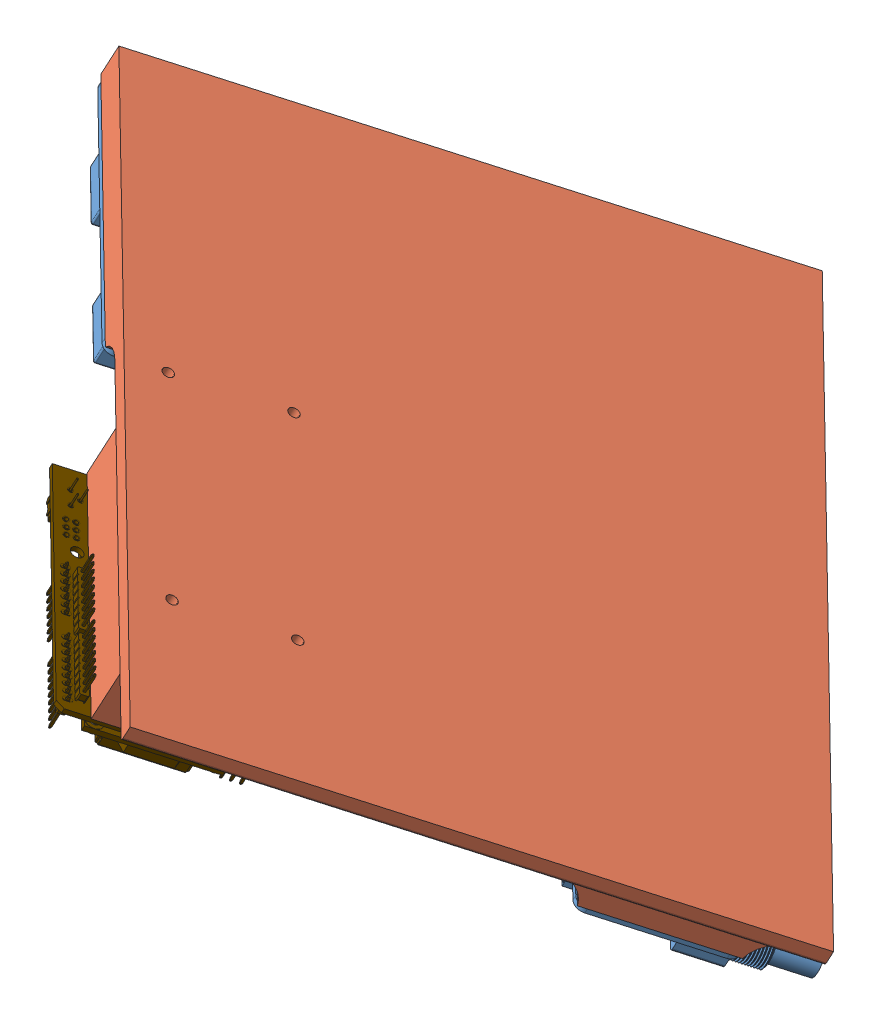
SolidWorks assembly growbox autorefill assembly, configuration Default. Lengths in mm.
Overall size (280.11 145.93 288.18).
73 component instances, 37 part files, 15 mates.
Components (placement in the parent):
- RelayClean.stp-1: RelayClean.stp [Default] at (-109.2702 -103.904 46.5137) x (0.587517 -0.410523 -0.697348) z (-0.706078 0.160923 -0.689606) size (177.8 17.08 90.17)
- growbox autorefill base-1: growbox autorefill base [Default] at (-84.2153 -124.6616 -49.3614) x (0.706078 -0.160923 0.689606) z (0.587517 -0.410523 -0.697348) size (224.54 40 180)
- Arduino MEGA 2560 R3.STEP-1: Arduino MEGA 2560 R3.STEP [Default] at (14.5549 -162.184 63.1118) x (0.706078 -0.160923 0.689606) z (0.587517 -0.410523 -0.697348) size (53.34 15.25 107.96)
  - MEGAboard.STEP-1: MEGAboard.STEP [Default] at origin size (53.34 1.6 101.6)
  - 47uf CAP Dcase.STEP-1: 47uf CAP Dcase.STEP [Default] at (-9.144 0 -18.415) x (0 0 -1) z (1 0 0) size (7.2 5.81 8)
  - USB SHELL.STEP-1: USB SHELL.STEP [Default] at (-38.02 0.43 6.35) size (14.09 15.2 16.51)
  - USB core.STEP-1: USB core.STEP [Default] at (-38.02 0.43 6.35) size (11.3 10.68 15.75)
  - usb top contact.STEP-1: usb top contact.STEP [Default] at (-36.77 6.52 5.97) size (1 9.67 13.76)
  - usb btm contact.STEP-1: usb btm contact.STEP [Default] at (-36.77 4.84 5.97) size (1 6.84 11.76)
  - usb btm contact.STEP-2: usb btm contact.STEP [Default] at (-39.27 4.84 5.97) size (1 6.84 11.76)
  - usb top contact.STEP-2: usb top contact.STEP [Default] at (-39.27 6.52 5.97) size (1 9.67 13.76)
  - power jack.STEP-1: power jack.STEP [Default] at (-7.675 0 1.905) size (11.2 15.2 15.9)
  - 47uf CAP Dcase.STEP-2: 47uf CAP Dcase.STEP [Default] at (-9.144 0 -25.527) x (0 0 -1) z (1 0 0) size (7.2 5.81 8)
  - crystal.STEP-1: crystal.STEP [Default] at (-26.035 0 -18.415) x (1 0 0) z (0 0 -1) size (4 5 11)
  - 2pin_header__02.STEP-1: 2pin_header__02.STEP [Default] at (-46.23 0 -15.75) size (5 11.75 2.54)
  - reg.STEP-1: reg.STEP [Default] at (-17.78 0 -8.636) size (6.5 1.69 8.3)
  - led.STEP-1: led.STEP [Default] at (-34.29 0 -27.94) x (0 0 1) z (-1 0 0) size (4.01 0.9 1.56)
  - 2pin_header__02.STEP-2: 2pin_header__02.STEP [Default] at (-30.43 0 -64.91) x (0 0 1) z (-1 0 0) size (5 11.75 2.54)
  - 2pin_header__02.STEP-3: 2pin_header__02.STEP [Default] at (-27.89 0 -64.91) x (0 0 1) z (-1 0 0) size (5 11.75 2.54)
  - 2pin_header__02.STEP-4: 2pin_header__02.STEP [Default] at (-25.35 0 -64.91) x (0 0 1) z (-1 0 0) size (5 11.75 2.54)
  - 2pin_header__02.STEP-5: 2pin_header__02.STEP [Default] at (-46.23 0 -18.29) size (5 11.75 2.54)
  - 2pin_header__02.STEP-6: 2pin_header__02.STEP [Default] at (-46.23 0 -20.83) size (5 11.75 2.54)
  - atmega16u2.STEP-1: atmega16u2.STEP [Default] at (-34.671 0.06 -20) x (1 0 0) z (0 0 -1) size (5.5 1.01 5.5)
  - led.STEP-2: led.STEP [Default] at (-36.576 0 -27.94) x (0 0 -1) z (1 0 0) size (4.01 0.9 1.56)
  - led.STEP-3: led.STEP [Default] at (-42.164 0 -27.94) x (0 0 1) z (-1 0 0) size (4.01 0.9 1.56)
  - led.STEP-4: led.STEP [Default] at (-36.83 0 -76.2) x (0 0 1) z (-1 0 0) size (4.01 0.9 1.56)
  - 8 PORT HEADER.STEP-1: 8 PORT HEADER.STEP [Default] at (-50.8 0 -45.72) x (0 0 -1) z (1 0 0) size (20.32 10.51 2.41)
  - 8 PORT HEADER.STEP-2: 8 PORT HEADER.STEP [Default] at (-2.54 0 -27.94) x (0 0 -1) z (1 0 0) size (20.32 10.51 2.41)
  - 8 PORT HEADER.STEP-3: 8 PORT HEADER.STEP [Default] at (-2.54 0 -50.8) x (0 0 -1) z (1 0 0) size (20.32 10.51 2.41)
  - 10 PORT HEADER.STEP-1: 10 PORT HEADER.STEP [Default] at (-50.8 0 -18.796) x (0 0 -1) z (1 0 0) size (25.4 10.51 2.41)
  - 102 RESISTOR PACK.STEP-1: 102 RESISTOR PACK.STEP [Default] at (-36.83 0 -80.645) size (3.2 0.51 3)
  - 102 RESISTOR PACK.STEP-2: 102 RESISTOR PACK.STEP [Default] at (-39.37 0 -27.94) size (3.2 0.51 3)
  - 103 RESISTOR PACK.STEP-1: 103 RESISTOR PACK.STEP [Default] at (-31.115 0 -27.94) size (3.2 0.51 3)
  - 220 RESISTOR PACK.STEP-1: 220 RESISTOR PACK.STEP [Default] at (-37.084 0 -12.065) size (3.2 0.51 3)
  - 16mhz crystal - measured.STEP-1: 16mhz crystal - measured.STEP [Default] at (-14.605 0 -38.354) size (3.4 0.8 2)
  - PADS001.STEP-1: PADS001.STEP [Default] at (-39.878 0.1 -18.288) x (-1 0 0) z (0 0 1) size (4.54 0.1 4.54)
  - 603 cap on pad.STEP-1: 603 cap on pad.STEP [Default] at (-44.45 0 -27.94) x (0 0 -1) z (1 0 0) size (2.76 0.9 1.02)
  - ssot3.STEP-1: ssot3.STEP [Default] at (-25.908 0 -9.144) x (-1 0 0) z (0 0 -1) size (3 1.13 3.09)
  - mf-msmf050-2.STEP-1: mf-msmf050-2.STEP [Default] at (-26.67 0 -4.445) size (6.12 1.1 3.72)
  - 603 cap on pad.STEP-2: 603 cap on pad.STEP [Default] at (-29.337 0 -24.765) x (0 0 1) z (-1 0 0) size (2.76 0.9 1.02)
  - 603 cap on pad.STEP-3: 603 cap on pad.STEP [Default] at (-30.988 0 -12.065) x (0 0 -1) z (1 0 0) size (2.76 0.9 1.02)
  - lmv358.STEP-1: lmv358.STEP [Default] at (-25.146 0 -27.94) size (3.7 1.4 2.9)
  - 603 cap on pad.STEP-4: 603 cap on pad.STEP [Default] at (-17.653 0 -14.351) size (2.76 0.9 1.02)
  - 603 cap on pad.STEP-5: 603 cap on pad.STEP [Default] at (-29.337 0 -12.065) x (0 0 1) z (-1 0 0) size (2.76 0.9 1.02)
  - 603 cap on pad.STEP-6: 603 cap on pad.STEP [Default] at (-29.337 0 -21.59) x (0 0 1) z (-1 0 0) size (2.76 0.9 1.02)
  - 603 cap on pad.STEP-7: 603 cap on pad.STEP [Default] at (-29.337 0 -15.24) x (0 0 1) z (-1 0 0) size (2.76 0.9 1.02)
  - 603 cap on pad.STEP-8: 603 cap on pad.STEP [Default] at (-42.291 0 -12.065) x (0 0 1) z (-1 0 0) size (2.76 0.9 1.02)
  - lp2985dgkr.STEP-1: lp2985dgkr.STEP [Default] at (-21.336 0 -18.415) x (0 0 -1) z (1 0 0) size (5.85 1.1 3)
  - cd1206 diode.STEP-1: cd1206 diode.STEP [Default] at (-14.605 0 -35.56) x (0 0 1) z (-1 0 0) size (2.01 0.96 5)
  - cd1206 diode.STEP-2: cd1206 diode.STEP [Default] at (-46.228 0 -13.081) x (0 0 1) z (-1 0 0) size (2.01 0.96 5)
  - 603 resistor.STEP-1: 603 resistor.STEP [Default] at (-29.337 0 -18.415) x (0 0 1) z (-1 0 0) size (2.36 0.61 1.02)
  - blm21.STEP-1: blm21.STEP [Default] at (-45.085 0 -8.255) x (0 0 -1) z (1 0 0) size (2.78 0.95 1.32)
  - m7 diode.STEP-1: m7 diode.STEP [Default] at (-2.794 0 -21.59) x (0 0 -1) z (1 0 0) size (6.66 2.35 2.5)
  - MLC0603.STEP-1: MLC0603.STEP [Default] at (-34.29 0 -12.065) x (0 0 -1) z (1 0 0) size (2.36 0.6 1.02)
  - MLC0603.STEP-2: MLC0603.STEP [Default] at (-39.878 0 -12.065) x (0 0 -1) z (1 0 0) size (2.36 0.6 1.02)
  - RESET CORE.STEP-1: RESET CORE.STEP [Default] at (-27.94 0.1 -74.168) x (0 0 1) z (-1 0 0) size (6.2 3.1 9.6)
  - RESET.STEP-1: RESET.STEP [Default] at (-27.94 0.1 -74.168) size (7.3 2 6.2)
  - 8 PORT HEADER.STEP-4: 8 PORT HEADER.STEP [Default] at (-2.54 0 -73.66) x (0 0 -1) z (1 0 0) size (20.32 10.51 2.41)
  - 8 PORT HEADER.STEP-5: 8 PORT HEADER.STEP [Default] at (-50.8 0 -68.58) x (0 0 -1) z (1 0 0) size (20.32 10.51 2.41)
  - 603 cap on pad.STEP-9: 603 cap on pad.STEP [Default] at (-21.59 0 -27.94) x (0 0 1) z (-1 0 0) size (2.76 0.9 1.02)
  - 603 cap on pad.STEP-10: 603 cap on pad.STEP [Default] at (-18.288 0 -27.94) x (0 0 1) z (-1 0 0) size (2.76 0.9 1.02)
  - 103 RESISTOR PACK.STEP-2: 103 RESISTOR PACK.STEP [Default] at (-16.51 0 -18.415) size (3.2 0.51 3)
  - 603 cap on pad.STEP-11: 603 cap on pad.STEP [Default] at (-17.145 0 -21.59) x (0 0 -1) z (1 0 0) size (2.76 0.9 1.02)
  - 603 cap on pad.STEP-12: 603 cap on pad.STEP [Default] at (-39.37 0 -58.928) x (0 0 1) z (-1 0 0) size (2.76 0.9 1.02)
  - 603 cap on pad.STEP-13: 603 cap on pad.STEP [Default] at (-14.605 0 -33.528) size (2.76 0.9 1.02)
  - 603 resistor.STEP-2: 603 resistor.STEP [Default] at (-14.605 0 -40.513) x (-1 0 0) z (0 0 -1) size (2.36 0.61 1.02)
  - 603 cap on pad.STEP-14: 603 cap on pad.STEP [Default] at (-7.112 0 -38.608) x (0 0 1) z (-1 0 0) size (2.76 0.9 1.02)
  - 603 cap on pad.STEP-15: 603 cap on pad.STEP [Default] at (-30.4038 0 -40.0558) x (0 0 1) z (-1 0 0) size (2.76 0.9 1.02)
  - 18 X 2 ROW HEADER.STEP-1: 18 X 2 ROW HEADER.STEP [Default] at (-50.8 0 -95.25) size (45.72 10.51 4.95)
  - atmega2650-16AU.STEP-1: atmega2650-16AU.STEP [Default] at (-28.3464 0.1 -50.8) x (0 0 1) z (-1 0 0) size (16.81 1.11 16.81)
- LCD_keypad_Shield_v1-1-2: LCD_keypad_Shield_v1-1 [Default] at (-86.8757 -128.7459 156.3462) x (0.706078 -0.160923 0.689606) z (0.587517 -0.410523 -0.697348) size (80 20.3 59)
- EC MEter DF Robot v1 v1.step-1: EC MEter DF Robot v1 v1.step [Default] at (17.1033 -153.7868 88.4256) x (-0.706078 0.160923 -0.689606) z (-0.395318 -0.897538 0.195317) size (32 65.71 12.6)
- EC MEter DF Robot v1 v1.step-2: EC MEter DF Robot v1 v1.step [Default] at (40.8397 -159.0694 112.193) x (-0.706078 0.160923 -0.689606) z (-0.395318 -0.897538 0.195317) size (32 65.71 12.6)
Mates (geometry in assembly coordinates):
- Coincident2: coincident anti-aligned: plane of RelayClean.stp-1 through (-109.2702 -103.904 46.5137) normal (0.395318 0.897538 -0.195317); plane of growbox autorefill base-1 through (-88.1685 -133.637 -47.4083) normal (-0.395318 -0.897538 0.195317)
- Coincident7: coincident anti-aligned: plane of growbox autorefill base-1 through (-90.1451 -138.1247 -46.4317) normal (-0.395318 -0.897538 0.195317); plane of Arduino MEGA 2560 R3.STEP-1/MEGAboard.STEP-1 through (-22.4748 -152.1643 26.0157) normal (0.395318 0.897538 -0.195317)
- Coincident13: coincident anti-aligned: line of growbox autorefill base-1 through (15.1874 -160.7479 62.7993) axis (-0.587517 0.410523 0.697348); line of Arduino MEGA 2560 R3.STEP-1/MEGAboard.STEP-1 through (-43.012 -120.0815 131.8786) axis (0.587517 -0.410523 -0.697348)
- Coincident14: coincident aligned: line of growbox autorefill base-1 through (15.1874 -160.7479 62.7993) axis (-0.706078 0.160923 -0.689606); line of Arduino MEGA 2560 R3.STEP-1/MEGAboard.STEP-1 through (15.1874 -160.7479 62.7993) axis (-0.706078 0.160923 -0.689606)
- Coincident15: coincident anti-aligned: line of RelayClean.stp-1 through (-131.9088 -74.1528 137.4094) axis (-0.706078 0.160923 -0.689606); line of growbox autorefill base-1 through (-193.3341 -60.1533 77.417) axis (0.706078 -0.160923 0.689606)
- Coincident16: coincident anti-aligned: line of RelayClean.stp-1 through (-191.4687 -61.4568 75.203) axis (0.587517 -0.410523 -0.697348); line of growbox autorefill base-1 through (-88.1685 -133.637 -47.4083) axis (-0.587517 0.410523 0.697348)
- Coincident18: coincident anti-aligned: plane of growbox autorefill base-1 through (-100.028 -160.5631 -41.5488) normal (-0.395318 -0.897538 0.195317); plane of LCD_keypad_Shield_v1-1-2 through (-99.4811 -127.5347 111.3338) normal (0.395318 0.897538 -0.195317)
- Concentric1: concentric aligned: circle of growbox autorefill base-1; circle of LCD_keypad_Shield_v1-1-2
- Parallel3: parallel aligned: line of growbox autorefill base-1 through (-129.2981 -106.8665 145.961) axis (0.587517 -0.410523 -0.697348); line of LCD_keypad_Shield_v1-1-2 through (-134.1446 -103.3138 152.4774) axis (0.587517 -0.410523 -0.697348)
- Concentric5: concentric aligned: circle of growbox autorefill base-1; circle of EC MEter DF Robot v1 v1.step-1
- Coincident21: coincident anti-aligned: plane of growbox autorefill base-1 through (-89.3544 -136.3296 -46.8223) normal (-0.395318 -0.897538 0.195317); plane of EC MEter DF Robot v1 v1.step-1 through (9.5167 -148.3543 98.0345) normal (0.395318 0.897538 -0.195317)
- Coincident22: coincident anti-aligned: plane of growbox autorefill base-1 through (-89.3544 -136.3296 -46.8223) normal (-0.395318 -0.897538 0.195317); plane of EC MEter DF Robot v1 v1.step-2 through (33.2531 -153.6368 121.8019) normal (0.395318 0.897538 -0.195317)
- Concentric9: concentric anti-aligned: cylinder of growbox autorefill base-1 through (14.1455 -144.4411 125.3854) axis (0.395318 0.897538 -0.195317) radius 1.6; cylinder of EC MEter DF Robot v1 v1.step-2 through (14.1455 -144.4411 125.3854) axis (-0.395318 -0.897538 0.195317) radius 1.5
- Parallel6: parallel anti-aligned: line of growbox autorefill base-1 through (57.1939 -164.9797 118.134) axis (-0.587517 0.410523 0.697348); line of EC MEter DF Robot v1 v1.step-2 through (33.9163 -148.7811 145.4576) axis (0.587517 -0.410523 -0.697348)
- Parallel7: parallel: line of growbox autorefill base-1 through (-14.083 -137.1168 101.9086) axis (0.706078 -0.160923 0.689606); plane of EC MEter DF Robot v1 v1.step-1 through (8.4173 -142.267 123.7823) normal (-0.587517 0.410523 0.697348)
